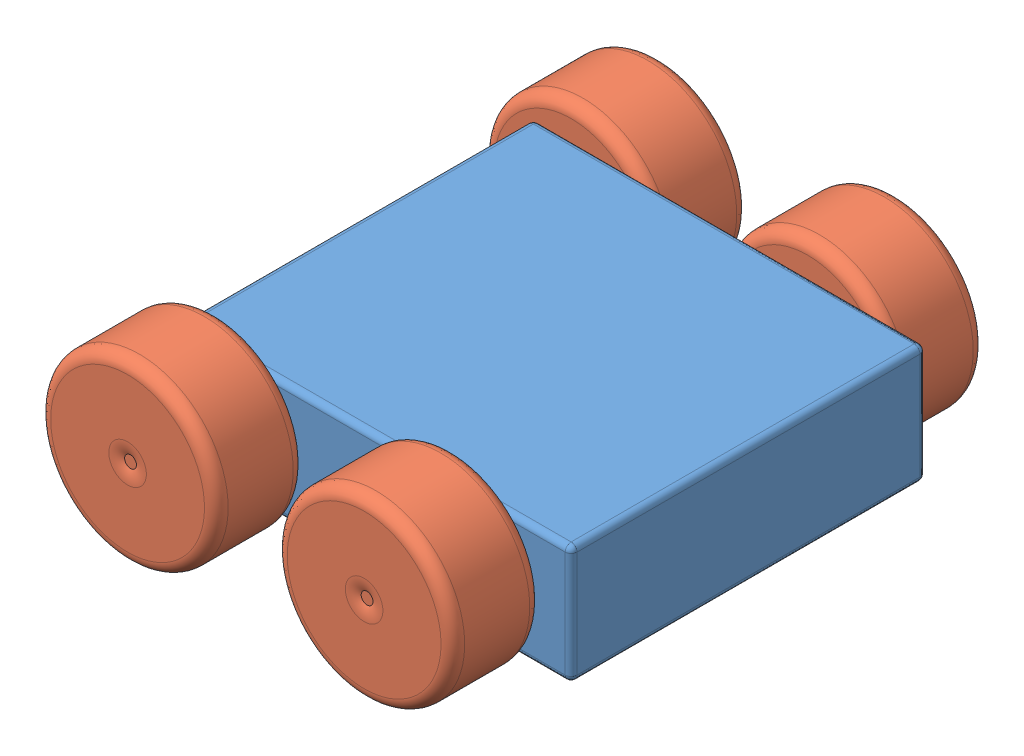
SolidWorks assembly R.PX0, configuration Default. Lengths in mm.
Overall size (800 384.12 900).
5 component instances, 2 part files, 8 mates.
Components (placement in the parent):
- P1-1: P1 [Default] at (-503.4971 155.1722 946.4364) x (1 0 0) z (0 -1 0) size (800 700 200)
- P2-1: P2 [Default] at (-703.4971 55.1722 496.4364) x (0.993585 -0.113083 0) z (0 0 1) size (300 300 150)
- P2-4: P2 [Default] at (-303.4971 55.1722 496.4364) x (0.961095 0.276219 0) z (0 0 1) size (300 300 150)
- P2-5: P2 [Default] at (-303.4971 55.1722 1396.4364) x (-0.940435 -0.339975 0) z (0 0 -1) size (300 300 150)
- P2-6: P2 [Default] at (-703.4971 55.1722 1396.4364) x (-0.999036 -0.043891 0) z (0 0 -1) size (300 300 150)
Mates (geometry in assembly coordinates):
- Concentric1: concentric aligned: cylinder of P1-1 through (-703.4971 55.1722 596.4364) axis (0 0 1) radius 30; cylinder of P2-1 through (-703.4971 55.1722 596.4364) axis (0 0 1) radius 30
- Coincident1: coincident anti-aligned: plane of P1-1 through (-703.4971 55.1722 596.4364) normal (0 0 -1); plane of P2-1 through (-703.4971 55.1722 596.4364) normal (0 0 1)
- Concentric2: concentric aligned: cylinder of P1-1 through (-303.4971 55.1722 596.4364) axis (0 0 1) radius 30; cylinder of P2-4 through (-303.4971 55.1722 596.4364) axis (0 0 1) radius 30
- Coincident2: coincident anti-aligned: plane of P1-1 through (-303.4971 55.1722 596.4364) normal (0 0 -1); plane of P2-4 through (-303.4971 55.1722 596.4364) normal (0 0 1)
- Concentric3: concentric aligned: cylinder of P1-1 through (-303.4971 55.1722 1296.4364) axis (0 0 -1) radius 30; cylinder of P2-5 through (-303.4971 55.1722 1296.4364) axis (0 0 -1) radius 30
- Coincident3: coincident anti-aligned: plane of P1-1 through (-303.4971 55.1722 1296.4364) normal (0 0 1); plane of P2-5 through (-303.4971 55.1722 1296.4364) normal (0 0 -1)
- Concentric4: concentric aligned: cylinder of P1-1 through (-703.4971 55.1722 1296.4364) axis (0 0 -1) radius 30; cylinder of P2-6 through (-703.4971 55.1722 1296.4364) axis (0 0 -1) radius 30
- Coincident4: coincident anti-aligned: plane of P1-1 through (-703.4971 55.1722 1296.4364) normal (0 0 1); plane of P2-6 through (-703.4971 55.1722 1296.4364) normal (0 0 -1)
